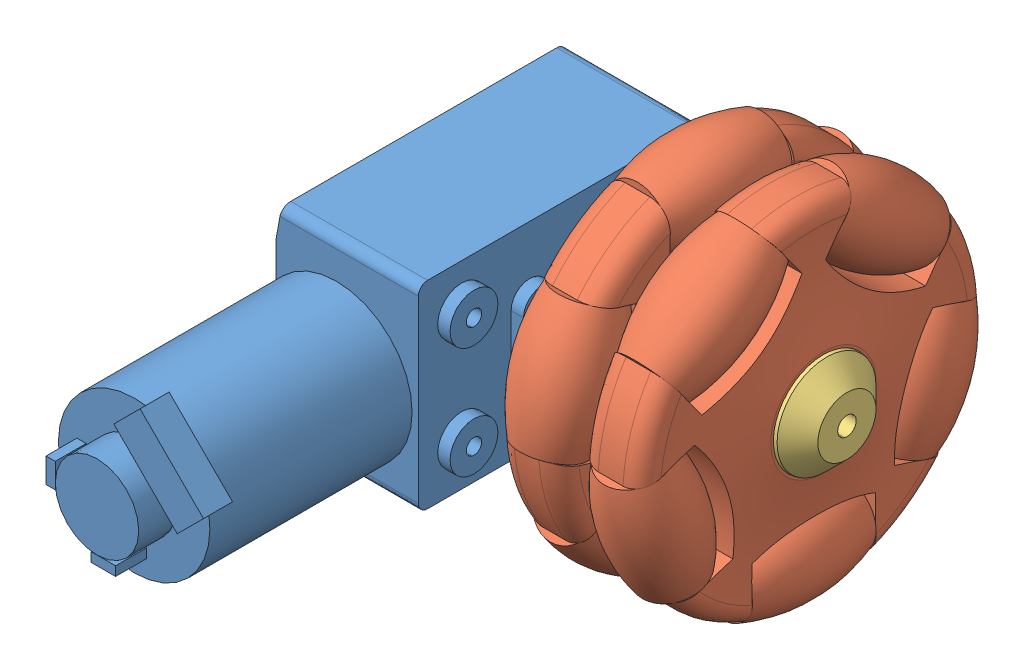
SolidWorks assembly omniwheel_steeldrive, configuration Default. Lengths in mm.
Overall size (63.8 58 98.7).
3 component instances, 3 part files, 7 mates.
Components (placement in the parent):
- motor_and_drive-1: motor_and_drive [Default] at origin size (41.8 32 84.7)
- omniwheel_shaftless-1: omniwheel_shaftless [Default] at (44.25 0 -8) size (27.1 58 58)
- omniwheel_adapter-1: omniwheel_adapter [Default] at (27.3 0 0) x (0 0 -1) z (1 0 0) size (16.2 16.2 34)
Mates (geometry in assembly coordinates):
- Concentric1: concentric aligned: circle of motor_and_drive-1; circle of omniwheel_shaftless-1
- Coincident1: coincident aligned: plane of omniwheel_shaftless-1 through (44.25 0 -8) normal (0 1 0); plane of assembly through (0 0 0) normal (0 1 0)
- Distance1: distance = 6 mm anti-aligned: plane of motor_and_drive-1 through (25 5 5) normal (1 0 0); plane of omniwheel_shaftless-1 through (31 0 -8) normal (-1 0 0)
- InPlace1: in place: plane of motor_and_drive-1 through (27.3 0 0) normal (1 0 0); plane of omniwheel_adapter-1 through (27.3 0 0) normal (1 0 0); moOrthogonalPlaneRef_w of motor_and_drive-1 through (27.3 0 0) normal (1 0 0); line of omniwheel_adapter-1 through (-55 27.3 0) axis (0 0 1); plane of motor_and_drive-1 through (27.3 0 0) normal (1 0 0); plane of omniwheel_adapter-1 through (27.3 0 0) normal (0 0 -1); plane of motor_and_drive-1 through (27.3 0 0) normal (1 0 0); unknown of omniwheel_adapter-1
- Coincident3: coincident aligned: plane of motor_and_drive-1; plane of omniwheel_adapter-1
- Coincident4: coincident aligned: moOrthogonalPlaneRef_w of motor_and_drive-1 through (27.3 0 0) normal (0 1 0); plane of omniwheel_adapter-1 through (27.3 0 0) normal (0 1 0)
- Coincident5: coincident anti-aligned: moOrthogonalPlaneRef_w of motor_and_drive-1 through (27.3 0 0) normal (0 0 1); plane of omniwheel_adapter-1 through (27.3 0 0) normal (0 0 -1)
